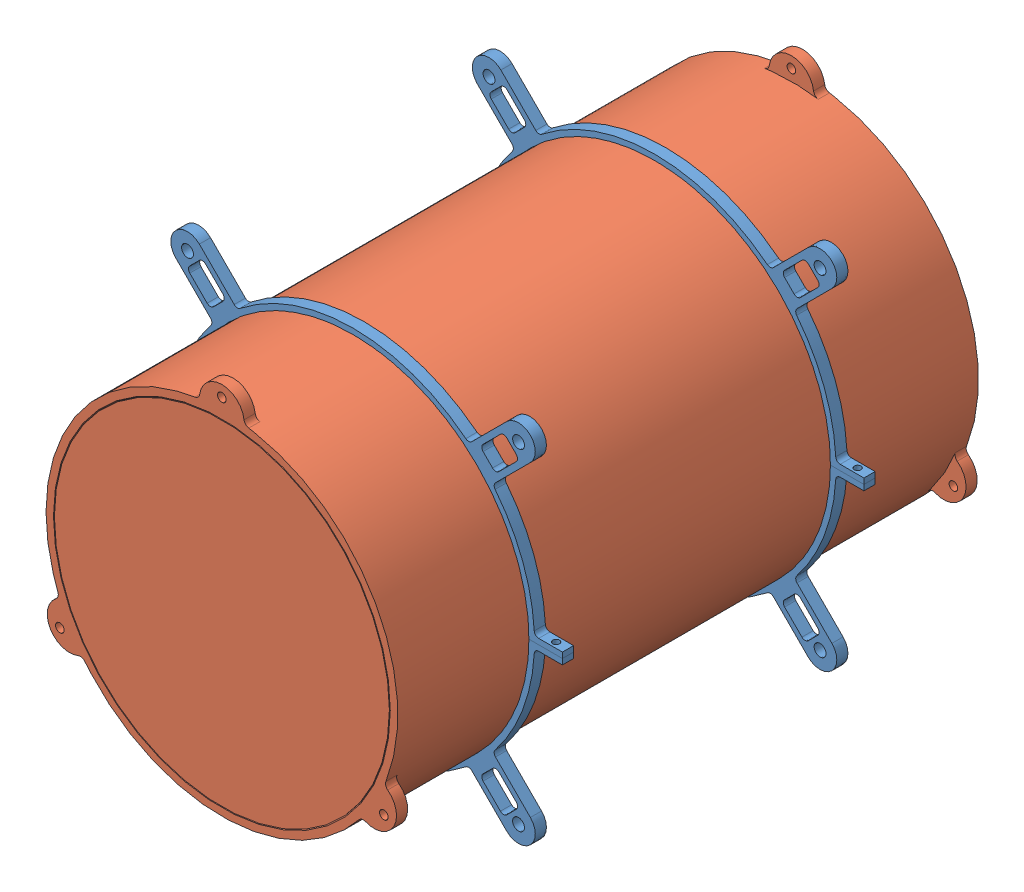
SolidWorks assembly Hull Clamped, configuration Default. Lengths in mm.
Overall size (238.18 216.35 330.2).
5 component instances, 2 part files, 8 mates.
Components (placement in the parent):
- Hull Clamp-1: Hull Clamp [Default] at (7.2546 -16.6715 -30.8819) size (238.18 103.64 6.35)
- main_hull-1: main_hull [Default] at (7.2546 -16.6715 -108.7146) size (200.03 212.72 330.2)
- Hull Clamp-2: Hull Clamp [Default] at (7.2546 -16.6715 -24.5319) x (1 0 0) z (0 0 -1) size (238.18 103.64 6.35)
- Hull Clamp-3: Hull Clamp [Default] at (7.2546 -16.6715 140.5681) size (238.18 103.64 6.35)
- Hull Clamp-4: Hull Clamp [Default] at (7.2546 -16.6715 146.9181) x (1 0 0) z (0 0 -1) size (238.18 103.64 6.35)
Mates (geometry in assembly coordinates):
- Coincident1: coincident anti-aligned: circle of Hull Clamp-3; circle of Hull Clamp-4
- Coincident2: coincident anti-aligned: circle of Hull Clamp-3; circle of Hull Clamp-4
- Concentric1: concentric aligned: cylinder of main_hull-1 through (7.2546 -16.6715 221.4854) axis (0 0 -1) radius 100.0125; cylinder of Hull Clamp-3 through (7.2546 -16.6715 146.9181) axis (0 0 -1) radius 100.0379
- Coincident3: coincident anti-aligned: circle of Hull Clamp-1; circle of Hull Clamp-2
- Coincident4: coincident anti-aligned: circle of Hull Clamp-1; circle of Hull Clamp-2
- Concentric2: concentric aligned: cylinder of Hull Clamp-1 through (7.2546 -16.6715 -24.5319) axis (0 0 -1) radius 100.0379; cylinder of main_hull-1 through (7.2546 -16.6715 221.4854) axis (0 0 -1) radius 100.0125
- Distance1: distance = 165.1 mm anti-aligned: plane of Hull Clamp-1 through (7.2546 -16.6715 -24.5319) normal (0 0 1); plane of Hull Clamp-3 through (7.2546 -16.6715 140.5681) normal (0 0 -1)
- Parallel1: parallel anti-aligned: line of main_hull-1 through (-92.7579 -16.6715 221.4854) axis (1 0 0); line of Hull Clamp-2 through (126.3425 -19.8465 -30.8819) axis (-1 0 0)
